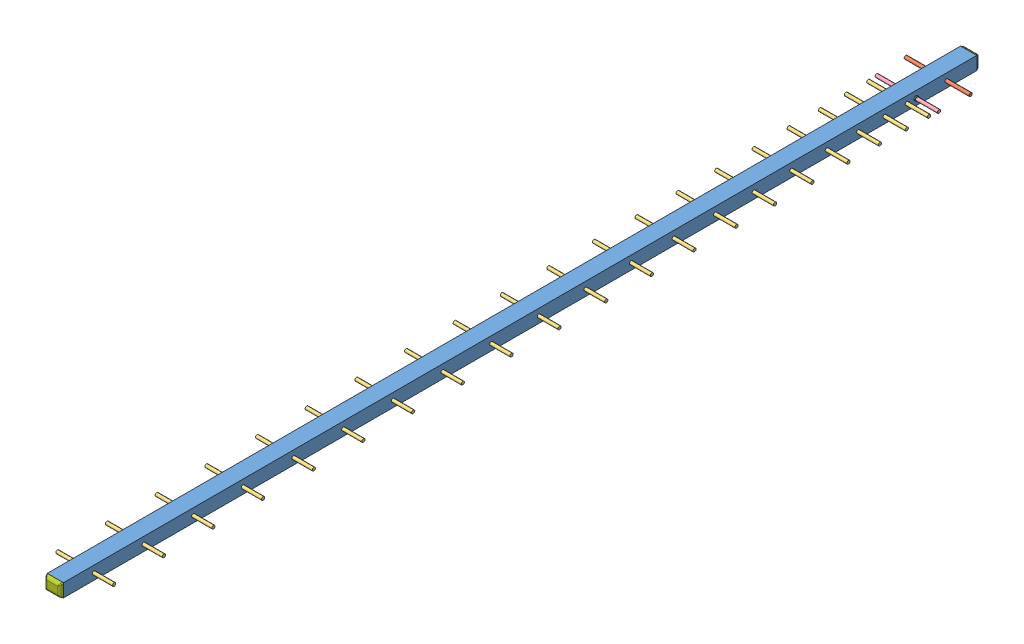
SolidWorks assembly Antenna, configuration Default. Lengths in mm.
Overall size (64 13 907).
29 component instances, 7 part files, 62 mates.
Components (placement in the parent):
- Boom-1: Boom [Default] at origin size (16 13 901)
- Reflector-1: Reflector [Default] at (0 0 -420.5) x (1 0 0) z (0 0 -1) size (64 3.17 3.17)
- Director-1: Director [1] at (0 0 -381.5) x (1 0 0) z (0 0 -1) size (60 3.17 3.17)
- Director-2: Director [2] at (0 0 -359.5) x (1 0 0) z (0 0 -1) size (60 3.17 3.17)
- Director-3: Director [3] at (0 0 -333.5) x (1 0 0) z (0 0 -1) size (59 3.17 3.17)
- Director-4: Director [4] at (0 0 -302.5) x (1 0 0) z (0 0 -1) size (59 3.17 3.17)
- Director-5: Director [5] at (0 0 -267.5) x (1 0 0) z (0 0 -1) size (58 3.17 3.17)
- Director-6: Director [6] at (0 0 -230.5) x (1 0 0) z (0 0 -1) size (58 3.17 3.17)
- Director-7: Director [7] at (0 0 -192.5) x (1 0 0) z (0 0 -1) size (58 3.17 3.17)
- Director-8: Director [8] at (0 0 -151.5) x (1 0 0) z (0 0 -1) size (57 3.17 3.17)
- Director-9: Director [9] at (0 0 -109.5) x (1 0 0) z (0 0 -1) size (57 3.17 3.17)
- Director-10: Director [10] at (0 0 -64.5) x (1 0 0) z (0 0 -1) size (57 3.17 3.17)
- Director-11: Director [11] at (0 0 -18.5) x (1 0 0) z (0 0 -1) size (57 3.17 3.17)
- Director-12: Director [12] at (0 0 28.5) x (1 0 0) z (0 0 -1) size (56 3.17 3.17)
- Director-13: Director [13] at (0 0 76.5) x (1 0 0) z (0 0 -1) size (56 3.17 3.17)
- Director-14: Director [14] at (0 0 125.5) x (1 0 0) z (0 0 -1) size (56 3.17 3.17)
- Director-15: Director [15] at (0 0 174.5) x (1 0 0) z (0 0 -1) size (56 3.17 3.17)
- Director-16: Director [16] at (0 0 223.5) x (1 0 0) z (0 0 -1) size (56 3.17 3.17)
- Director-17: Director [17] at (0 0 273.5) x (1 0 0) z (0 0 -1) size (56 3.17 3.17)
- Director-18: Director [18] at (0 0 322.5) x (1 0 0) z (0 0 -1) size (56 3.17 3.17)
- Director-19: Director [19] at (0 0 371.5) x (1 0 0) z (0 0 -1) size (56 3.17 3.17)
- Director-20: Director [20] at (0 0 420.5) x (1 0 0) z (0 0 -1) size (56 3.17 3.17)
- Radiator-1: Radiator [Default] at (15.6271 0 -390.5) size (30.25 3.17 3.17)
- Radiator-2: Radiator [Default] at (-15.6271 0 -390.5) size (30.25 3.17 3.17)
- Dipole Holder-1: Dipole Holder [Default] at (0 0 -390.5) x (0 0 1) z (-1 0 0) size (12.5 5.7 12.5)
- Dipole Isolator-1: Dipole Isolator [Default] at (-6.75 0 -390.5) x (-1 0 0) z (0 0 -1) size (5 4.2 4.2)
- End Cap-1: End Cap [Default] at (0 -0.8 450.5) x (-1 0 0) z (0 0 -1) size (16 13 8)
- Dipole Isolator-2: Dipole Isolator [Default] at (6.75 0 -390.5) size (5 4.2 4.2)
- End Cap-2: End Cap [Default] at (0 -0.8 -450.5) size (16 13 8)
Mates (geometry in assembly coordinates):
- Concentric1: concentric: cylinder of Boom-1 through (-8 0 -420.5) axis (1 0 0) radius 1.5875; cylinder of Reflector-1 through (32 0 -420.5) axis (-1 0 0) radius 1.5875
- Coincident1: coincident: plane of Boom-1 through (0 0 0) normal (0 0 1); plane of assembly through (0 0 0) normal (0 0 1)
- Coincident2: coincident: plane of Boom-1 through (0 0 0) normal (0 1 0); plane of assembly through (0 0 0) normal (0 1 0)
- Coincident3: coincident: plane of Boom-1 through (0 0 0) normal (1 0 0); plane of assembly through (0 0 0) normal (1 0 0)
- Coincident4: coincident: plane of Reflector-1 through (0 0 -420.5) normal (1 0 0); plane of assembly through (0 0 0) normal (1 0 0)
- Concentric2: concentric: cylinder of Boom-1 through (-8 0 -381.5) axis (1 0 0) radius 1.5875; cylinder of Director-1 through (30 0 -381.5) axis (-1 0 0) radius 1.5875
- Concentric3: concentric: cylinder of Boom-1 through (-8 0 -359.5) axis (1 0 0) radius 1.5875; cylinder of Director-2 through (30 0 -359.5) axis (-1 0 0) radius 1.5875
- Concentric4: concentric: cylinder of Boom-1 through (-8 0 -333.5) axis (1 0 0) radius 1.5875; cylinder of Director-3 through (29.5 0 -333.5) axis (-1 0 0) radius 1.5875
- Concentric5: concentric: cylinder of Boom-1 through (-8 0 -302.5) axis (1 0 0) radius 1.5875; cylinder of Director-4 through (29.5 0 -302.5) axis (-1 0 0) radius 1.5875
- Concentric6: concentric: cylinder of Boom-1 through (-8 0 -267.5) axis (1 0 0) radius 1.5875; cylinder of Director-5 through (29 0 -267.5) axis (-1 0 0) radius 1.5875
- Concentric7: concentric: cylinder of Boom-1 through (-8 0 -230.5) axis (1 0 0) radius 1.5875; cylinder of Director-6 through (29 0 -230.5) axis (-1 0 0) radius 1.5875
- Concentric8: concentric: cylinder of Boom-1 through (-8 0 -192.5) axis (1 0 0) radius 1.5875; cylinder of Director-7 through (29 0 -192.5) axis (-1 0 0) radius 1.5875
- Concentric9: concentric: cylinder of Boom-1 through (-8 0 -151.5) axis (1 0 0) radius 1.5875; cylinder of Director-8 through (28.5 0 -151.5) axis (-1 0 0) radius 1.5875
- Concentric10: concentric: cylinder of Boom-1 through (-8 0 -109.5) axis (1 0 0) radius 1.5875; cylinder of Director-9 through (28.5 0 -109.5) axis (-1 0 0) radius 1.5875
- Concentric11: concentric: cylinder of Boom-1 through (-8 0 -64.5) axis (1 0 0) radius 1.5875; cylinder of Director-10 through (28.5 0 -64.5) axis (-1 0 0) radius 1.5875
- Concentric12: concentric: cylinder of Boom-1 through (-8 0 -18.5) axis (1 0 0) radius 1.5875; cylinder of Director-11 through (28.5 0 -18.5) axis (-1 0 0) radius 1.5875
- Concentric13: concentric: cylinder of Boom-1 through (-8 0 28.5) axis (1 0 0) radius 1.5875; cylinder of Director-12 through (28 0 28.5) axis (-1 0 0) radius 1.5875
- Concentric14: concentric: cylinder of Boom-1 through (-8 0 76.5) axis (1 0 0) radius 1.5875; cylinder of Director-13 through (28 0 76.5) axis (-1 0 0) radius 1.5875
- Concentric15: concentric: cylinder of Boom-1 through (-8 0 125.5) axis (1 0 0) radius 1.5875; cylinder of Director-14 through (28 0 125.5) axis (-1 0 0) radius 1.5875
- Concentric16: concentric: cylinder of Boom-1 through (-8 0 174.5) axis (1 0 0) radius 1.5875; cylinder of Director-15 through (28 0 174.5) axis (-1 0 0) radius 1.5875
- Concentric17: concentric: cylinder of Boom-1 through (-8 0 223.5) axis (1 0 0) radius 1.5875; cylinder of Director-16 through (28 0 223.5) axis (-1 0 0) radius 1.5875
- Concentric18: concentric: cylinder of Boom-1 through (-8 0 273.5) axis (1 0 0) radius 1.5875; cylinder of Director-17 through (28 0 273.5) axis (-1 0 0) radius 1.5875
- Concentric19: concentric: cylinder of Boom-1 through (-8 0 322.5) axis (1 0 0) radius 1.5875; cylinder of Director-18 through (28 0 322.5) axis (-1 0 0) radius 1.5875
- Concentric20: concentric: cylinder of Boom-1 through (-8 0 371.5) axis (1 0 0) radius 1.5875; cylinder of Director-19 through (28 0 371.5) axis (-1 0 0) radius 1.5875
- Concentric21: concentric: cylinder of Boom-1 through (-8 0 420.5) axis (1 0 0) radius 1.5875; cylinder of Director-20 through (28 0 420.5) axis (-1 0 0) radius 1.5875
- Coincident8: coincident: plane of Director-1 through (0 0 -381.5) normal (1 0 0); plane of assembly through (0 0 0) normal (1 0 0)
- Coincident9: coincident: plane of Director-2 through (0 0 -359.5) normal (1 0 0); plane of assembly through (0 0 0) normal (1 0 0)
- Coincident10: coincident: plane of Director-3 through (0 0 -333.5) normal (1 0 0); plane of assembly through (0 0 0) normal (1 0 0)
- Coincident11: coincident: plane of Director-4 through (0 0 -302.5) normal (1 0 0); plane of assembly through (0 0 0) normal (1 0 0)
- Coincident12: coincident: plane of Director-5 through (0 0 -267.5) normal (1 0 0); plane of assembly through (0 0 0) normal (1 0 0)
- Coincident13: coincident: plane of Director-6 through (0 0 -230.5) normal (1 0 0); plane of assembly through (0 0 0) normal (1 0 0)
- Coincident14: coincident: plane of Director-7 through (0 0 -192.5) normal (1 0 0); plane of assembly through (0 0 0) normal (1 0 0)
- Coincident15: coincident: plane of Director-8 through (0 0 -151.5) normal (1 0 0); plane of assembly through (0 0 0) normal (1 0 0)
- Coincident16: coincident: plane of Director-9 through (0 0 -109.5) normal (1 0 0); plane of assembly through (0 0 0) normal (1 0 0)
- Coincident17: coincident: plane of Director-10 through (0 0 -64.5) normal (1 0 0); plane of assembly through (0 0 0) normal (1 0 0)
- Coincident18: coincident: plane of Director-11 through (0 0 -18.5) normal (1 0 0); plane of assembly through (0 0 0) normal (1 0 0)
- Coincident19: coincident: plane of Director-12 through (0 0 28.5) normal (1 0 0); plane of assembly through (0 0 0) normal (1 0 0)
- Coincident20: coincident: plane of Director-13 through (0 0 76.5) normal (1 0 0); plane of assembly through (0 0 0) normal (1 0 0)
- Coincident21: coincident: plane of Director-14 through (0 0 125.5) normal (1 0 0); plane of assembly through (0 0 0) normal (1 0 0)
- Coincident22: coincident: plane of Director-15 through (0 0 174.5) normal (1 0 0); plane of assembly through (0 0 0) normal (1 0 0)
- Coincident23: coincident: plane of Director-16 through (0 0 223.5) normal (1 0 0); plane of assembly through (0 0 0) normal (1 0 0)
- Coincident24: coincident: plane of Director-17 through (0 0 273.5) normal (1 0 0); plane of assembly through (0 0 0) normal (1 0 0)
- Coincident25: coincident: plane of Director-18 through (0 0 322.5) normal (1 0 0); plane of assembly through (0 0 0) normal (1 0 0)
- Coincident26: coincident: plane of Director-19 through (0 0 371.5) normal (1 0 0); plane of assembly through (0 0 0) normal (1 0 0)
- Coincident27: coincident: plane of Director-20 through (0 0 420.5) normal (1 0 0); plane of assembly through (0 0 0) normal (1 0 0)
- Concentric22: concentric: cylinder of Radiator-1 through (30.7543 0 -390.5) axis (-1 0 0) radius 1.5875; cylinder of Radiator-2 through (-0.5 0 -390.5) axis (-1 0 0) radius 1.5875
- Concentric23: concentric: cylinder of Boom-1 through (-8 0 -390.5) axis (1 0 0) radius 2.1; cylinder of Radiator-1 through (30.7543 0 -390.5) axis (-1 0 0) radius 1.5875
- Distance1: distance = 1 mm: plane of Radiator-2 through (-0.5 0 -390.5) normal (1 0 0); plane of Radiator-1 through (0.5 0 -390.5) normal (-1 0 0)
- Width1: width: plane of Radiator-2 through (-0.5 0 -390.5) normal (1 0 0); plane of Radiator-1 through (0.5 0 -390.5) normal (-1 0 0); plane of Boom-1 through (-6.4 4.9 450.5) normal (1 0 0); plane of Boom-1 through (6.4 -6.5 450.5) normal (-1 0 0)
- Coincident28: coincident: plane of Boom-1 through (0 0 450.5) normal (0 0 1); plane of End Cap-1 through (0 -0.8 450.5) normal (0 0 -1)
- Coincident32: coincident: plane of Boom-1 through (6.4 4.9 450.5) normal (0 -1 0); plane of End Cap-1 through (6.4 4.9 445.5) normal (0 1 0)
- Width3: width: plane of End Cap-1 through (-6.4 -6.5 445.5) normal (-1 0 0); plane of End Cap-1 through (6.4 -6.5 445.5) normal (1 0 0); plane of Boom-1 through (8 6.5 450.5) normal (1 0 0); plane of Boom-1 through (-8 -6.5 450.5) normal (-1 0 0)
- Coincident33: coincident: plane of Boom-1 through (6.4 4.9 450.5) normal (0 -1 0); plane of End Cap-2 through (0.8 4.9 -445.5) normal (0 1 0)
- Width5: width: plane of End Cap-2 through (-6.4 -6.5 -445.5) normal (-1 0 0); plane of End Cap-2 through (6.4 -6.5 -445.5) normal (1 0 0); plane of Boom-1 through (-8 -6.5 450.5) normal (-1 0 0); plane of Boom-1 through (8 6.5 450.5) normal (1 0 0)
- Coincident29: coincident: plane of Boom-1 through (0 0 -450.5) normal (0 0 -1); plane of End Cap-2 through (7.2 -0.8 -450.5) normal (0 0 1)
- Concentric24: concentric: cylinder of Dipole Holder-1 through (-4.25 0 -390.5) axis (-1 0 0) radius 2.1; cylinder of Dipole Isolator-1 through (-9.25 0 -390.5) axis (1 0 0) radius 2.1
- Coincident30: coincident: plane of Dipole Holder-1 through (-4.25 0 -390.5) normal (-1 0 0); plane of Dipole Isolator-1 through (-4.25 0 -390.5) normal (1 0 0)
- Concentric25: concentric: cylinder of Dipole Holder-1 through (4.25 0 -390.5) axis (1 0 0) radius 2.1; cylinder of Dipole Isolator-2 through (9.25 0 -390.5) axis (-1 0 0) radius 2.1
- Coincident31: coincident: plane of Dipole Holder-1 through (4.25 0 -390.5) normal (1 0 0); plane of Dipole Isolator-2 through (4.25 0 -390.5) normal (-1 0 0)
- Width6: width: plane of Dipole Holder-1 through (-6.25 4.7 -396.75) normal (-1 0 0); plane of Dipole Holder-1 through (6.25 4.7 -396.75) normal (1 0 0); plane of Boom-1 through (-6.4 4.9 450.5) normal (1 0 0); plane of Boom-1 through (6.4 -6.5 450.5) normal (-1 0 0)
- Parallel1: parallel: plane of Dipole Holder-1 through (0 4.7 -390.5) normal (0 1 0); plane of Boom-1 through (6.4 4.9 450.5) normal (0 -1 0)
- Concentric26: concentric: cylinder of Radiator-1 through (30.7543 0 -390.5) axis (-1 0 0) radius 1.5875; cylinder of Dipole Isolator-2 through (9.25 0 -390.5) axis (-1 0 0) radius 2.1
